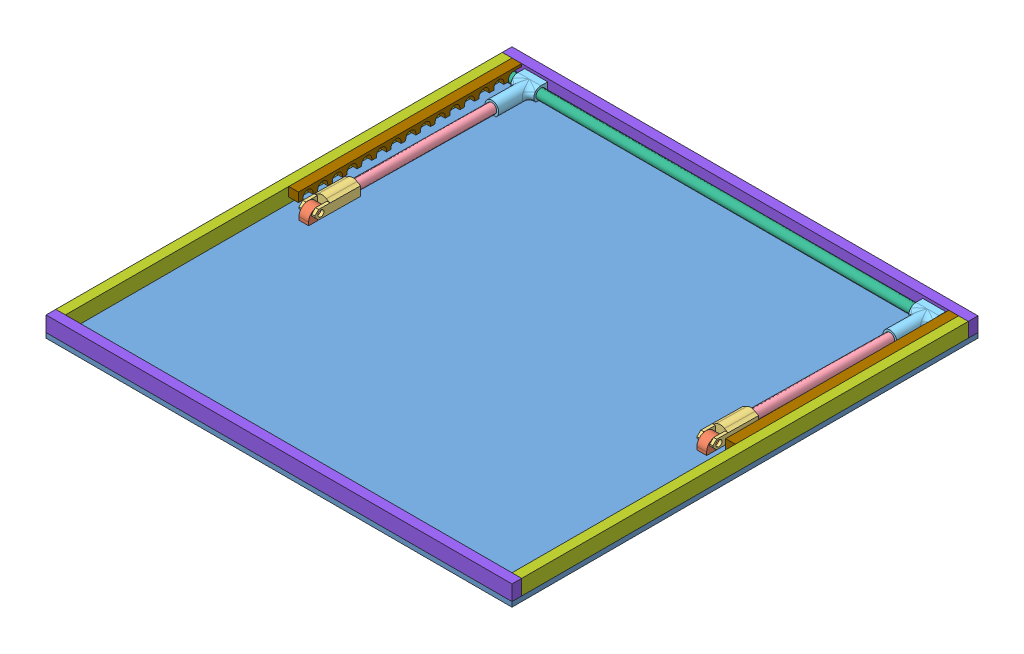
SolidWorks assembly tabletop v2, configuration Default. Lengths in mm.
Overall size (304.8 13.23 304.82).
17 component instances, 9 part files, 13 mates.
Components (placement in the parent):
- Tabletop-1: Tabletop [Default] at origin size (304.8 3.17 304.8)
- Leg_AttatchV2-1: Leg_AttatchV2 [Default] at (-133.35 5.175 6) x (0 0 -1) z (1 0 0) size (12 8 6.35)
- Leg_AttatchV2-2: Leg_AttatchV2 [Default] at (127 5.175 6) x (0 0 -1) z (1 0 0) size (12 8 6.35)
- Leg_Adapter-1: Leg_Adapter [Default] at (-130.175 7.8466 -25.9979) x (1 0 0) z (0 0.012629 0.99992) size (10.35 10 30)
- Leg_Adapter-2: Leg_Adapter [Default] at (130.175 7.8466 -25.9979) x (1 0 0) z (0 0.012629 0.99992) size (10.35 10 30)
- Leg_v2-1: Leg_v2 [Default] at (130.175 6.4448 -136.9891) x (0.583854 -0.811794 0.010253) z (0 0.012629 0.99992) size (6.35 6.35 126)
- Leg_v2-2: Leg_v2 [Default] at (-130.175 8.0361 -10.9991) x (-0.583854 -0.811794 0.010253) z (0 -0.012629 -0.99992) size (6.35 6.35 126)
- Crossbar Adaptor-1: Crossbar Adaptor [Default] at (122.675 6.388 -141.4887) x (0 0.99992 -0.012629) z (1 0 0) size (9 29 15)
- Crossbar Adaptor-2: Crossbar Adaptor [Default] at (-137.675 6.388 -141.4887) x (0 0.99992 -0.012629) z (1 0 0) size (9 29 15)
- Crossbar_v2-1: Crossbar_v2 [Default] at (146.05 6.388 -141.4887) x (0 -0.987363 0.158473) z (-1 0 0) size (6.35 6.35 292.1)
- Frame_Subassm-1: Frame_Subassm [Default] at (146.05 7.9165 -0.0083) x (0 0.001696 0.999999) z (1 0 0) size (304.8 10 304.8)
  - DepthFrame-1: DepthFrame [Default] at origin size (292.1 10 6.35)
  - WidthFrame-2: WidthFrame [Default] at (146.05 0 -146.05) x (0 0 1) z (0 1 0) size (304.8 6.35 10)
  - DepthFrame-2: DepthFrame [Default] at (0 0 -298.45) size (292.1 10 6.35)
  - WidthFrame-3: WidthFrame [Default] at (-146.05 0 -146.05) x (0 0 1) z (0 -1 0) size (304.8 6.35 10)
  - Slots-1: Slots [Default] at (-146.05 -5 -6.35) size (146.05 6 6.35)
  - Slots-2: Slots [Default] at (-146.05 -5 -292.1) size (146.05 6 6.35)
Mates (geometry in assembly coordinates):
- Coincident1: coincident anti-aligned: plane of Tabletop-1 through (0 3.175 0) normal (0 1 0); plane of Leg_AttatchV2-1 through (-133.35 3.175 6) normal (0 -1 0)
- Coincident2: coincident anti-aligned: line of Tabletop-1 through (-127 3.175 0) axis (0 0 -1); line of Leg_AttatchV2-1 through (-127 3.175 -6) axis (0 0 1)
- Coincident3: coincident aligned: line of Tabletop-1 through (-138.2527 3.175 -6) axis (1 0 0); line of Leg_AttatchV2-1 through (-133.35 3.175 -6) axis (1 0 0)
- Concentric1: concentric aligned: cylinder of Leg_AttatchV2-1 through (-127 8.175 0) axis (-1 0 0) radius 2; cylinder of Leg_Adapter-1 through (-125 8.175 0) axis (-1 0 0) radius 2
- Width1: width anti-aligned: plane of Leg_Adapter-1 through (-133.35 4.767 -32.2841) normal (1 0 0); plane of Leg_AttatchV2-1 through (-127 4.767 -32.2841) normal (-1 0 0); plane of Leg_Adapter-1 through (-133.35 5.175 0) normal (-1 0 0); plane of Leg_AttatchV2-1 through (-127 5.175 0) normal (1 0 0)
- Concentric2: concentric aligned: cylinder of Leg_Adapter-2 through (130.175 8.0361 -10.9991) axis (0 -0.012629 -0.99992) radius 3; cylinder of Leg_v2-1 through (130.175 8.0361 -10.9991) axis (0 -0.012629 -0.99992) radius 3.175
- Coincident4: coincident anti-aligned: plane of Leg_Adapter-2 through (130.175 8.0361 -10.9991) normal (0 -0.012629 -0.99992); plane of Leg_v2-1 through (130.175 8.0361 -10.9991) normal (0 0.012629 0.99992)
- Concentric3: concentric aligned: cylinder of Leg_v2-1 through (130.175 8.0361 -10.9991) axis (0 -0.012629 -0.99992) radius 3.175; cylinder of Crossbar Adaptor-1 through (130.175 6.6974 -116.9907) axis (0 -0.012629 -0.99992) radius 2.5
- Coincident5: coincident anti-aligned: plane of Leg_v2-1 through (130.175 6.4448 -136.9891) normal (0 -0.012629 -0.99992); plane of Crossbar Adaptor-1 through (130.175 6.4448 -136.9891) normal (0 0.012629 0.99992)
- Concentric8: concentric anti-aligned: cylinder of Crossbar Adaptor-1 through (137.675 6.388 -141.4887) axis (-1 0 0) radius 2.5; cylinder of Crossbar_v2-1 through (-146.05 6.388 -141.4887) axis (1 0 0) radius 3.175
- Width2: width anti-aligned: plane of Tabletop-1 through (152.4 3.175 -152.4) normal (1 0 0); plane of Crossbar_v2-1 through (-152.4 3.175 -152.4) normal (-1 0 0); plane of Tabletop-1 through (-146.05 6.388 -141.4887) normal (-1 0 0); plane of Crossbar_v2-1 through (146.05 6.388 -141.4887) normal (1 0 0)
- Coincident6: coincident aligned: line of Tabletop-1 through (-152.4 3.175 152.4) axis (1 0 0); line of Frame_Subassm-1/WidthFrame-2 through (-152.4 3.175 152.4) axis (1 0 0)
- Width3: width anti-aligned: plane of Frame_Subassm-1/DepthFrame-2 through (-152.4 7.9165 -0.0083) normal (-1 0 0); plane of Tabletop-1 through (152.4 7.9165 -0.0083) normal (1 0 0); plane of Frame_Subassm-1/DepthFrame-1 through (152.4 3.175 -152.4) normal (1 0 0); plane of Tabletop-1 through (-152.4 3.175 -152.4) normal (-1 0 0)
